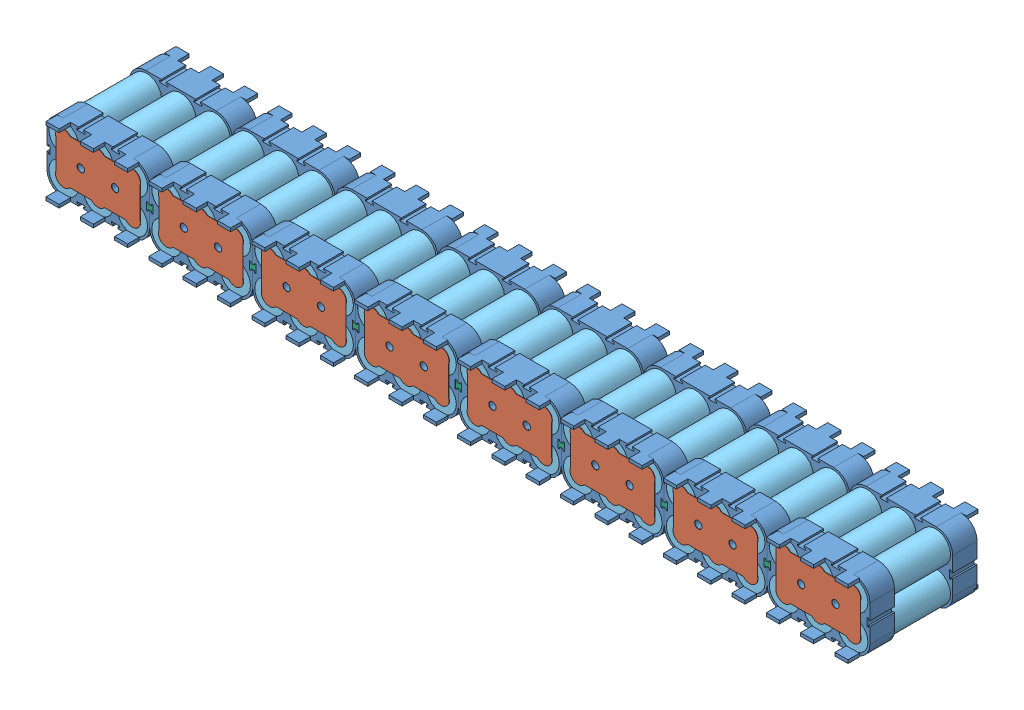
SolidWorks assembly 1S24P_Brick, configuration Default. Lengths in mm.
Overall size (511.31 49.31 71.6).
239 component instances, 6 part files, 3 mates.
Components (placement in the parent):
- 6P_Cell_Pack-1: 6P_Cell_Pack [Default] at origin size (70.31 49.31 71.6)
  - Cell_Holder_6P-1: Cell_Holder_6P [Default] at origin size (63 42 18)
  - Cell_Holder_6P-2: Cell_Holder_6P [Default] at (63 0 -35.6) x (-1 0 0) z (0 0 -1) size (63 42 18)
  - Contact_Plate-1: Contact_Plate [Default] at (5.5 5.515 15) x (1 0 0) z (0 -1 0) size (52 0.2 30.97)
  - Contact_Plate-2: Contact_Plate [Default] at (5.5 5.515 -50.8) x (1 0 0) z (0 -1 0) size (52 0.2 30.97)
  - 18650_wrapped-1: 18650_wrapped [Default] at (10.5 31.5 14.75) x (0.990631 -0.136562 0) z (0.136562 0.990631 0) size (25.12 65.6 25.12)
    - 18650-1: 18650 [Default] at origin size (18 65 18)
    - Insulator_donut-1: Insulator_donut [Default] at (0 64.8 0) x (0.970599 0 -0.240704) z (0.240704 0 0.970599) size (18 0.3 18)
    - 18650_Shrinkwarp-1: 18650_Shrinkwarp [Default] x (0.480873 0 0.87679) z (-0.87679 0 0.480873) size (18.5 65.6 18.5)
  - 18650_wrapped-2: 18650_wrapped [Default] at (31.5 31.5 14.75) x (0.990631 -0.136562 0) z (0.136562 0.990631 0) size (25.12 65.6 25.12)
    - 18650-1: 18650 [Default] at origin size (18 65 18)
    - Insulator_donut-1: Insulator_donut [Default] at (0 64.8 0) x (0.970599 0 -0.240704) z (0.240704 0 0.970599) size (18 0.3 18)
    - 18650_Shrinkwarp-1: 18650_Shrinkwarp [Default] x (0.480873 0 0.87679) z (-0.87679 0 0.480873) size (18.5 65.6 18.5)
  - 18650_wrapped-3: 18650_wrapped [Default] at (52.5 31.5 14.75) x (0.990631 -0.136562 0) z (0.136562 0.990631 0) size (25.12 65.6 25.12)
    - 18650-1: 18650 [Default] at origin size (18 65 18)
    - Insulator_donut-1: Insulator_donut [Default] at (0 64.8 0) x (0.970599 0 -0.240704) z (0.240704 0 0.970599) size (18 0.3 18)
    - 18650_Shrinkwarp-1: 18650_Shrinkwarp [Default] x (0.480873 0 0.87679) z (-0.87679 0 0.480873) size (18.5 65.6 18.5)
  - 18650_wrapped-4: 18650_wrapped [Default] at (10.5 10.5 14.75) x (0.990631 -0.136562 0) z (0.136562 0.990631 0) size (25.12 65.6 25.12)
    - 18650-1: 18650 [Default] at origin size (18 65 18)
    - Insulator_donut-1: Insulator_donut [Default] at (0 64.8 0) x (0.970599 0 -0.240704) z (0.240704 0 0.970599) size (18 0.3 18)
    - 18650_Shrinkwarp-1: 18650_Shrinkwarp [Default] x (0.480873 0 0.87679) z (-0.87679 0 0.480873) size (18.5 65.6 18.5)
  - 18650_wrapped-5: 18650_wrapped [Default] at (31.5 10.5 14.75) x (0.990631 -0.136562 0) z (0.136562 0.990631 0) size (25.12 65.6 25.12)
    - 18650-1: 18650 [Default] at origin size (18 65 18)
    - Insulator_donut-1: Insulator_donut [Default] at (0 64.8 0) x (0.970599 0 -0.240704) z (0.240704 0 0.970599) size (18 0.3 18)
    - 18650_Shrinkwarp-1: 18650_Shrinkwarp [Default] x (0.480873 0 0.87679) z (-0.87679 0 0.480873) size (18.5 65.6 18.5)
  - 18650_wrapped-6: 18650_wrapped [Default] at (52.5 10.5 14.75) x (0.990631 -0.136562 0) z (0.136562 0.990631 0) size (25.12 65.6 25.12)
    - 18650-1: 18650 [Default] at origin size (18 65 18)
    - Insulator_donut-1: Insulator_donut [Default] at (0 64.8 0) x (0.970599 0 -0.240704) z (0.240704 0 0.970599) size (18 0.3 18)
    - 18650_Shrinkwarp-1: 18650_Shrinkwarp [Default] x (0.480873 0 0.87679) z (-0.87679 0 0.480873) size (18.5 65.6 18.5)
- 6P_Cell_Pack-3: 6P_Cell_Pack [Default] at (-63 0 0) size (70.31 49.31 71.6)
  - Cell_Holder_6P-1: Cell_Holder_6P [Default] at origin size (63 42 18)
  - Cell_Holder_6P-2: Cell_Holder_6P [Default] at (63 0 -35.6) x (-1 0 0) z (0 0 -1) size (63 42 18)
  - Contact_Plate-1: Contact_Plate [Default] at (5.5 5.515 15) x (1 0 0) z (0 -1 0) size (52 0.2 30.97)
  - Contact_Plate-2: Contact_Plate [Default] at (5.5 5.515 -50.8) x (1 0 0) z (0 -1 0) size (52 0.2 30.97)
  - 18650_wrapped-1: 18650_wrapped [Default] at (10.5 31.5 14.75) x (0.990631 -0.136562 0) z (0.136562 0.990631 0) size (25.12 65.6 25.12)
    - 18650-1: 18650 [Default] at origin size (18 65 18)
    - Insulator_donut-1: Insulator_donut [Default] at (0 64.8 0) x (0.970599 0 -0.240704) z (0.240704 0 0.970599) size (18 0.3 18)
    - 18650_Shrinkwarp-1: 18650_Shrinkwarp [Default] x (0.480873 0 0.87679) z (-0.87679 0 0.480873) size (18.5 65.6 18.5)
  - 18650_wrapped-2: 18650_wrapped [Default] at (31.5 31.5 14.75) x (0.990631 -0.136562 0) z (0.136562 0.990631 0) size (25.12 65.6 25.12)
    - 18650-1: 18650 [Default] at origin size (18 65 18)
    - Insulator_donut-1: Insulator_donut [Default] at (0 64.8 0) x (0.970599 0 -0.240704) z (0.240704 0 0.970599) size (18 0.3 18)
    - 18650_Shrinkwarp-1: 18650_Shrinkwarp [Default] x (0.480873 0 0.87679) z (-0.87679 0 0.480873) size (18.5 65.6 18.5)
  - 18650_wrapped-3: 18650_wrapped [Default] at (52.5 31.5 14.75) x (0.990631 -0.136562 0) z (0.136562 0.990631 0) size (25.12 65.6 25.12)
    - 18650-1: 18650 [Default] at origin size (18 65 18)
    - Insulator_donut-1: Insulator_donut [Default] at (0 64.8 0) x (0.970599 0 -0.240704) z (0.240704 0 0.970599) size (18 0.3 18)
    - 18650_Shrinkwarp-1: 18650_Shrinkwarp [Default] x (0.480873 0 0.87679) z (-0.87679 0 0.480873) size (18.5 65.6 18.5)
  - 18650_wrapped-4: 18650_wrapped [Default] at (10.5 10.5 14.75) x (0.990631 -0.136562 0) z (0.136562 0.990631 0) size (25.12 65.6 25.12)
    - 18650-1: 18650 [Default] at origin size (18 65 18)
    - Insulator_donut-1: Insulator_donut [Default] at (0 64.8 0) x (0.970599 0 -0.240704) z (0.240704 0 0.970599) size (18 0.3 18)
    - 18650_Shrinkwarp-1: 18650_Shrinkwarp [Default] x (0.480873 0 0.87679) z (-0.87679 0 0.480873) size (18.5 65.6 18.5)
  - 18650_wrapped-5: 18650_wrapped [Default] at (31.5 10.5 14.75) x (0.990631 -0.136562 0) z (0.136562 0.990631 0) size (25.12 65.6 25.12)
    - 18650-1: 18650 [Default] at origin size (18 65 18)
    - Insulator_donut-1: Insulator_donut [Default] at (0 64.8 0) x (0.970599 0 -0.240704) z (0.240704 0 0.970599) size (18 0.3 18)
    - 18650_Shrinkwarp-1: 18650_Shrinkwarp [Default] x (0.480873 0 0.87679) z (-0.87679 0 0.480873) size (18.5 65.6 18.5)
  - 18650_wrapped-6: 18650_wrapped [Default] at (52.5 10.5 14.75) x (0.990631 -0.136562 0) z (0.136562 0.990631 0) size (25.12 65.6 25.12)
    - 18650-1: 18650 [Default] at origin size (18 65 18)
    - Insulator_donut-1: Insulator_donut [Default] at (0 64.8 0) x (0.970599 0 -0.240704) z (0.240704 0 0.970599) size (18 0.3 18)
    - 18650_Shrinkwarp-1: 18650_Shrinkwarp [Default] x (0.480873 0 0.87679) z (-0.87679 0 0.480873) size (18.5 65.6 18.5)
- 6P_Cell_Pack-4: 6P_Cell_Pack [Default] at (-126 0 0) size (70.31 49.31 71.6)
  - Cell_Holder_6P-1: Cell_Holder_6P [Default] at origin size (63 42 18)
  - Cell_Holder_6P-2: Cell_Holder_6P [Default] at (63 0 -35.6) x (-1 0 0) z (0 0 -1) size (63 42 18)
  - Contact_Plate-1: Contact_Plate [Default] at (5.5 5.515 15) x (1 0 0) z (0 -1 0) size (52 0.2 30.97)
  - Contact_Plate-2: Contact_Plate [Default] at (5.5 5.515 -50.8) x (1 0 0) z (0 -1 0) size (52 0.2 30.97)
  - 18650_wrapped-1: 18650_wrapped [Default] at (10.5 31.5 14.75) x (0.990631 -0.136562 0) z (0.136562 0.990631 0) size (25.12 65.6 25.12)
    - 18650-1: 18650 [Default] at origin size (18 65 18)
    - Insulator_donut-1: Insulator_donut [Default] at (0 64.8 0) x (0.970599 0 -0.240704) z (0.240704 0 0.970599) size (18 0.3 18)
    - 18650_Shrinkwarp-1: 18650_Shrinkwarp [Default] x (0.480873 0 0.87679) z (-0.87679 0 0.480873) size (18.5 65.6 18.5)
  - 18650_wrapped-2: 18650_wrapped [Default] at (31.5 31.5 14.75) x (0.990631 -0.136562 0) z (0.136562 0.990631 0) size (25.12 65.6 25.12)
    - 18650-1: 18650 [Default] at origin size (18 65 18)
    - Insulator_donut-1: Insulator_donut [Default] at (0 64.8 0) x (0.970599 0 -0.240704) z (0.240704 0 0.970599) size (18 0.3 18)
    - 18650_Shrinkwarp-1: 18650_Shrinkwarp [Default] x (0.480873 0 0.87679) z (-0.87679 0 0.480873) size (18.5 65.6 18.5)
  - 18650_wrapped-3: 18650_wrapped [Default] at (52.5 31.5 14.75) x (0.990631 -0.136562 0) z (0.136562 0.990631 0) size (25.12 65.6 25.12)
    - 18650-1: 18650 [Default] at origin size (18 65 18)
    - Insulator_donut-1: Insulator_donut [Default] at (0 64.8 0) x (0.970599 0 -0.240704) z (0.240704 0 0.970599) size (18 0.3 18)
    - 18650_Shrinkwarp-1: 18650_Shrinkwarp [Default] x (0.480873 0 0.87679) z (-0.87679 0 0.480873) size (18.5 65.6 18.5)
  - 18650_wrapped-4: 18650_wrapped [Default] at (10.5 10.5 14.75) x (0.990631 -0.136562 0) z (0.136562 0.990631 0) size (25.12 65.6 25.12)
    - 18650-1: 18650 [Default] at origin size (18 65 18)
    - Insulator_donut-1: Insulator_donut [Default] at (0 64.8 0) x (0.970599 0 -0.240704) z (0.240704 0 0.970599) size (18 0.3 18)
    - 18650_Shrinkwarp-1: 18650_Shrinkwarp [Default] x (0.480873 0 0.87679) z (-0.87679 0 0.480873) size (18.5 65.6 18.5)
  - 18650_wrapped-5: 18650_wrapped [Default] at (31.5 10.5 14.75) x (0.990631 -0.136562 0) z (0.136562 0.990631 0) size (25.12 65.6 25.12)
    - 18650-1: 18650 [Default] at origin size (18 65 18)
    - Insulator_donut-1: Insulator_donut [Default] at (0 64.8 0) x (0.970599 0 -0.240704) z (0.240704 0 0.970599) size (18 0.3 18)
    - 18650_Shrinkwarp-1: 18650_Shrinkwarp [Default] x (0.480873 0 0.87679) z (-0.87679 0 0.480873) size (18.5 65.6 18.5)
  - 18650_wrapped-6: 18650_wrapped [Default] at (52.5 10.5 14.75) x (0.990631 -0.136562 0) z (0.136562 0.990631 0) size (25.12 65.6 25.12)
    - 18650-1: 18650 [Default] at origin size (18 65 18)
    - Insulator_donut-1: Insulator_donut [Default] at (0 64.8 0) x (0.970599 0 -0.240704) z (0.240704 0 0.970599) size (18 0.3 18)
    - 18650_Shrinkwarp-1: 18650_Shrinkwarp [Default] x (0.480873 0 0.87679) z (-0.87679 0 0.480873) size (18.5 65.6 18.5)
- 6P_Cell_Pack-5: 6P_Cell_Pack [Default] at (-189 0 0) size (70.31 49.31 71.6)
  - Cell_Holder_6P-1: Cell_Holder_6P [Default] at origin size (63 42 18)
  - Cell_Holder_6P-2: Cell_Holder_6P [Default] at (63 0 -35.6) x (-1 0 0) z (0 0 -1) size (63 42 18)
  - Contact_Plate-1: Contact_Plate [Default] at (5.5 5.515 15) x (1 0 0) z (0 -1 0) size (52 0.2 30.97)
  - Contact_Plate-2: Contact_Plate [Default] at (5.5 5.515 -50.8) x (1 0 0) z (0 -1 0) size (52 0.2 30.97)
  - 18650_wrapped-1: 18650_wrapped [Default] at (10.5 31.5 14.75) x (0.990631 -0.136562 0) z (0.136562 0.990631 0) size (25.12 65.6 25.12)
    - 18650-1: 18650 [Default] at origin size (18 65 18)
    - Insulator_donut-1: Insulator_donut [Default] at (0 64.8 0) x (0.970599 0 -0.240704) z (0.240704 0 0.970599) size (18 0.3 18)
    - 18650_Shrinkwarp-1: 18650_Shrinkwarp [Default] x (0.480873 0 0.87679) z (-0.87679 0 0.480873) size (18.5 65.6 18.5)
  - 18650_wrapped-2: 18650_wrapped [Default] at (31.5 31.5 14.75) x (0.990631 -0.136562 0) z (0.136562 0.990631 0) size (25.12 65.6 25.12)
    - 18650-1: 18650 [Default] at origin size (18 65 18)
    - Insulator_donut-1: Insulator_donut [Default] at (0 64.8 0) x (0.970599 0 -0.240704) z (0.240704 0 0.970599) size (18 0.3 18)
    - 18650_Shrinkwarp-1: 18650_Shrinkwarp [Default] x (0.480873 0 0.87679) z (-0.87679 0 0.480873) size (18.5 65.6 18.5)
  - 18650_wrapped-3: 18650_wrapped [Default] at (52.5 31.5 14.75) x (0.990631 -0.136562 0) z (0.136562 0.990631 0) size (25.12 65.6 25.12)
    - 18650-1: 18650 [Default] at origin size (18 65 18)
    - Insulator_donut-1: Insulator_donut [Default] at (0 64.8 0) x (0.970599 0 -0.240704) z (0.240704 0 0.970599) size (18 0.3 18)
    - 18650_Shrinkwarp-1: 18650_Shrinkwarp [Default] x (0.480873 0 0.87679) z (-0.87679 0 0.480873) size (18.5 65.6 18.5)
  - 18650_wrapped-4: 18650_wrapped [Default] at (10.5 10.5 14.75) x (0.990631 -0.136562 0) z (0.136562 0.990631 0) size (25.12 65.6 25.12)
    - 18650-1: 18650 [Default] at origin size (18 65 18)
    - Insulator_donut-1: Insulator_donut [Default] at (0 64.8 0) x (0.970599 0 -0.240704) z (0.240704 0 0.970599) size (18 0.3 18)
    - 18650_Shrinkwarp-1: 18650_Shrinkwarp [Default] x (0.480873 0 0.87679) z (-0.87679 0 0.480873) size (18.5 65.6 18.5)
  - 18650_wrapped-5: 18650_wrapped [Default] at (31.5 10.5 14.75) x (0.990631 -0.136562 0) z (0.136562 0.990631 0) size (25.12 65.6 25.12)
    - 18650-1: 18650 [Default] at origin size (18 65 18)
    - Insulator_donut-1: Insulator_donut [Default] at (0 64.8 0) x (0.970599 0 -0.240704) z (0.240704 0 0.970599) size (18 0.3 18)
    - 18650_Shrinkwarp-1: 18650_Shrinkwarp [Default] x (0.480873 0 0.87679) z (-0.87679 0 0.480873) size (18.5 65.6 18.5)
  - 18650_wrapped-6: 18650_wrapped [Default] at (52.5 10.5 14.75) x (0.990631 -0.136562 0) z (0.136562 0.990631 0) size (25.12 65.6 25.12)
    - 18650-1: 18650 [Default] at origin size (18 65 18)
    - Insulator_donut-1: Insulator_donut [Default] at (0 64.8 0) x (0.970599 0 -0.240704) z (0.240704 0 0.970599) size (18 0.3 18)
    - 18650_Shrinkwarp-1: 18650_Shrinkwarp [Default] x (0.480873 0 0.87679) z (-0.87679 0 0.480873) size (18.5 65.6 18.5)
- 6P_Cell_Pack-6: 6P_Cell_Pack [Default] at (-252 0 0) size (70.31 49.31 71.6)
  - Cell_Holder_6P-1: Cell_Holder_6P [Default] at origin size (63 42 18)
  - Cell_Holder_6P-2: Cell_Holder_6P [Default] at (63 0 -35.6) x (-1 0 0) z (0 0 -1) size (63 42 18)
  - Contact_Plate-1: Contact_Plate [Default] at (5.5 5.515 15) x (1 0 0) z (0 -1 0) size (52 0.2 30.97)
  - Contact_Plate-2: Contact_Plate [Default] at (5.5 5.515 -50.8) x (1 0 0) z (0 -1 0) size (52 0.2 30.97)
  - 18650_wrapped-1: 18650_wrapped [Default] at (10.5 31.5 14.75) x (0.990631 -0.136562 0) z (0.136562 0.990631 0) size (25.12 65.6 25.12)
    - 18650-1: 18650 [Default] at origin size (18 65 18)
    - Insulator_donut-1: Insulator_donut [Default] at (0 64.8 0) x (0.970599 0 -0.240704) z (0.240704 0 0.970599) size (18 0.3 18)
    - 18650_Shrinkwarp-1: 18650_Shrinkwarp [Default] x (0.480873 0 0.87679) z (-0.87679 0 0.480873) size (18.5 65.6 18.5)
  - 18650_wrapped-2: 18650_wrapped [Default] at (31.5 31.5 14.75) x (0.990631 -0.136562 0) z (0.136562 0.990631 0) size (25.12 65.6 25.12)
    - 18650-1: 18650 [Default] at origin size (18 65 18)
    - Insulator_donut-1: Insulator_donut [Default] at (0 64.8 0) x (0.970599 0 -0.240704) z (0.240704 0 0.970599) size (18 0.3 18)
    - 18650_Shrinkwarp-1: 18650_Shrinkwarp [Default] x (0.480873 0 0.87679) z (-0.87679 0 0.480873) size (18.5 65.6 18.5)
  - 18650_wrapped-3: 18650_wrapped [Default] at (52.5 31.5 14.75) x (0.990631 -0.136562 0) z (0.136562 0.990631 0) size (25.12 65.6 25.12)
    - 18650-1: 18650 [Default] at origin size (18 65 18)
    - Insulator_donut-1: Insulator_donut [Default] at (0 64.8 0) x (0.970599 0 -0.240704) z (0.240704 0 0.970599) size (18 0.3 18)
    - 18650_Shrinkwarp-1: 18650_Shrinkwarp [Default] x (0.480873 0 0.87679) z (-0.87679 0 0.480873) size (18.5 65.6 18.5)
  - 18650_wrapped-4: 18650_wrapped [Default] at (10.5 10.5 14.75) x (0.990631 -0.136562 0) z (0.136562 0.990631 0) size (25.12 65.6 25.12)
    - 18650-1: 18650 [Default] at origin size (18 65 18)
    - Insulator_donut-1: Insulator_donut [Default] at (0 64.8 0) x (0.970599 0 -0.240704) z (0.240704 0 0.970599) size (18 0.3 18)
    - 18650_Shrinkwarp-1: 18650_Shrinkwarp [Default] x (0.480873 0 0.87679) z (-0.87679 0 0.480873) size (18.5 65.6 18.5)
  - 18650_wrapped-5: 18650_wrapped [Default] at (31.5 10.5 14.75) x (0.990631 -0.136562 0) z (0.136562 0.990631 0) size (25.12 65.6 25.12)
    - 18650-1: 18650 [Default] at origin size (18 65 18)
    - Insulator_donut-1: Insulator_donut [Default] at (0 64.8 0) x (0.970599 0 -0.240704) z (0.240704 0 0.970599) size (18 0.3 18)
    - 18650_Shrinkwarp-1: 18650_Shrinkwarp [Default] x (0.480873 0 0.87679) z (-0.87679 0 0.480873) size (18.5 65.6 18.5)
  - 18650_wrapped-6: 18650_wrapped [Default] at (52.5 10.5 14.75) x (0.990631 -0.136562 0) z (0.136562 0.990631 0) size (25.12 65.6 25.12)
    - 18650-1: 18650 [Default] at origin size (18 65 18)
    - Insulator_donut-1: Insulator_donut [Default] at (0 64.8 0) x (0.970599 0 -0.240704) z (0.240704 0 0.970599) size (18 0.3 18)
    - 18650_Shrinkwarp-1: 18650_Shrinkwarp [Default] x (0.480873 0 0.87679) z (-0.87679 0 0.480873) size (18.5 65.6 18.5)
- 6P_Cell_Pack-7: 6P_Cell_Pack [Default] at (-315 0 0) size (70.31 49.31 71.6)
  - Cell_Holder_6P-1: Cell_Holder_6P [Default] at origin size (63 42 18)
  - Cell_Holder_6P-2: Cell_Holder_6P [Default] at (63 0 -35.6) x (-1 0 0) z (0 0 -1) size (63 42 18)
  - Contact_Plate-1: Contact_Plate [Default] at (5.5 5.515 15) x (1 0 0) z (0 -1 0) size (52 0.2 30.97)
  - Contact_Plate-2: Contact_Plate [Default] at (5.5 5.515 -50.8) x (1 0 0) z (0 -1 0) size (52 0.2 30.97)
  - 18650_wrapped-1: 18650_wrapped [Default] at (10.5 31.5 14.75) x (0.990631 -0.136562 0) z (0.136562 0.990631 0) size (25.12 65.6 25.12)
    - 18650-1: 18650 [Default] at origin size (18 65 18)
    - Insulator_donut-1: Insulator_donut [Default] at (0 64.8 0) x (0.970599 0 -0.240704) z (0.240704 0 0.970599) size (18 0.3 18)
    - 18650_Shrinkwarp-1: 18650_Shrinkwarp [Default] x (0.480873 0 0.87679) z (-0.87679 0 0.480873) size (18.5 65.6 18.5)
  - 18650_wrapped-2: 18650_wrapped [Default] at (31.5 31.5 14.75) x (0.990631 -0.136562 0) z (0.136562 0.990631 0) size (25.12 65.6 25.12)
    - 18650-1: 18650 [Default] at origin size (18 65 18)
    - Insulator_donut-1: Insulator_donut [Default] at (0 64.8 0) x (0.970599 0 -0.240704) z (0.240704 0 0.970599) size (18 0.3 18)
    - 18650_Shrinkwarp-1: 18650_Shrinkwarp [Default] x (0.480873 0 0.87679) z (-0.87679 0 0.480873) size (18.5 65.6 18.5)
  - 18650_wrapped-3: 18650_wrapped [Default] at (52.5 31.5 14.75) x (0.990631 -0.136562 0) z (0.136562 0.990631 0) size (25.12 65.6 25.12)
    - 18650-1: 18650 [Default] at origin size (18 65 18)
    - Insulator_donut-1: Insulator_donut [Default] at (0 64.8 0) x (0.970599 0 -0.240704) z (0.240704 0 0.970599) size (18 0.3 18)
    - 18650_Shrinkwarp-1: 18650_Shrinkwarp [Default] x (0.480873 0 0.87679) z (-0.87679 0 0.480873) size (18.5 65.6 18.5)
  - 18650_wrapped-4: 18650_wrapped [Default] at (10.5 10.5 14.75) x (0.990631 -0.136562 0) z (0.136562 0.990631 0) size (25.12 65.6 25.12)
    - 18650-1: 18650 [Default] at origin size (18 65 18)
    - Insulator_donut-1: Insulator_donut [Default] at (0 64.8 0) x (0.970599 0 -0.240704) z (0.240704 0 0.970599) size (18 0.3 18)
    - 18650_Shrinkwarp-1: 18650_Shrinkwarp [Default] x (0.480873 0 0.87679) z (-0.87679 0 0.480873) size (18.5 65.6 18.5)
  - 18650_wrapped-5: 18650_wrapped [Default] at (31.5 10.5 14.75) x (0.990631 -0.136562 0) z (0.136562 0.990631 0) size (25.12 65.6 25.12)
    - 18650-1: 18650 [Default] at origin size (18 65 18)
    - Insulator_donut-1: Insulator_donut [Default] at (0 64.8 0) x (0.970599 0 -0.240704) z (0.240704 0 0.970599) size (18 0.3 18)
    - 18650_Shrinkwarp-1: 18650_Shrinkwarp [Default] x (0.480873 0 0.87679) z (-0.87679 0 0.480873) size (18.5 65.6 18.5)
  - 18650_wrapped-6: 18650_wrapped [Default] at (52.5 10.5 14.75) x (0.990631 -0.136562 0) z (0.136562 0.990631 0) size (25.12 65.6 25.12)
    - 18650-1: 18650 [Default] at origin size (18 65 18)
    - Insulator_donut-1: Insulator_donut [Default] at (0 64.8 0) x (0.970599 0 -0.240704) z (0.240704 0 0.970599) size (18 0.3 18)
    - 18650_Shrinkwarp-1: 18650_Shrinkwarp [Default] x (0.480873 0 0.87679) z (-0.87679 0 0.480873) size (18.5 65.6 18.5)
- 6P_Cell_Pack-8: 6P_Cell_Pack [Default] at (-378 0 0) size (70.31 49.31 71.6)
  - Cell_Holder_6P-1: Cell_Holder_6P [Default] at origin size (63 42 18)
  - Cell_Holder_6P-2: Cell_Holder_6P [Default] at (63 0 -35.6) x (-1 0 0) z (0 0 -1) size (63 42 18)
  - Contact_Plate-1: Contact_Plate [Default] at (5.5 5.515 15) x (1 0 0) z (0 -1 0) size (52 0.2 30.97)
  - Contact_Plate-2: Contact_Plate [Default] at (5.5 5.515 -50.8) x (1 0 0) z (0 -1 0) size (52 0.2 30.97)
  - 18650_wrapped-1: 18650_wrapped [Default] at (10.5 31.5 14.75) x (0.990631 -0.136562 0) z (0.136562 0.990631 0) size (25.12 65.6 25.12)
    - 18650-1: 18650 [Default] at origin size (18 65 18)
    - Insulator_donut-1: Insulator_donut [Default] at (0 64.8 0) x (0.970599 0 -0.240704) z (0.240704 0 0.970599) size (18 0.3 18)
    - 18650_Shrinkwarp-1: 18650_Shrinkwarp [Default] x (0.480873 0 0.87679) z (-0.87679 0 0.480873) size (18.5 65.6 18.5)
  - 18650_wrapped-2: 18650_wrapped [Default] at (31.5 31.5 14.75) x (0.990631 -0.136562 0) z (0.136562 0.990631 0) size (25.12 65.6 25.12)
    - 18650-1: 18650 [Default] at origin size (18 65 18)
    - Insulator_donut-1: Insulator_donut [Default] at (0 64.8 0) x (0.970599 0 -0.240704) z (0.240704 0 0.970599) size (18 0.3 18)
    - 18650_Shrinkwarp-1: 18650_Shrinkwarp [Default] x (0.480873 0 0.87679) z (-0.87679 0 0.480873) size (18.5 65.6 18.5)
  - 18650_wrapped-3: 18650_wrapped [Default] at (52.5 31.5 14.75) x (0.990631 -0.136562 0) z (0.136562 0.990631 0) size (25.12 65.6 25.12)
    - 18650-1: 18650 [Default] at origin size (18 65 18)
    - Insulator_donut-1: Insulator_donut [Default] at (0 64.8 0) x (0.970599 0 -0.240704) z (0.240704 0 0.970599) size (18 0.3 18)
    - 18650_Shrinkwarp-1: 18650_Shrinkwarp [Default] x (0.480873 0 0.87679) z (-0.87679 0 0.480873) size (18.5 65.6 18.5)
  - 18650_wrapped-4: 18650_wrapped [Default] at (10.5 10.5 14.75) x (0.990631 -0.136562 0) z (0.136562 0.990631 0) size (25.12 65.6 25.12)
    - 18650-1: 18650 [Default] at origin size (18 65 18)
    - Insulator_donut-1: Insulator_donut [Default] at (0 64.8 0) x (0.970599 0 -0.240704) z (0.240704 0 0.970599) size (18 0.3 18)
    - 18650_Shrinkwarp-1: 18650_Shrinkwarp [Default] x (0.480873 0 0.87679) z (-0.87679 0 0.480873) size (18.5 65.6 18.5)
  - 18650_wrapped-5: 18650_wrapped [Default] at (31.5 10.5 14.75) x (0.990631 -0.136562 0) z (0.136562 0.990631 0) size (25.12 65.6 25.12)
    - 18650-1: 18650 [Default] at origin size (18 65 18)
    - Insulator_donut-1: Insulator_donut [Default] at (0 64.8 0) x (0.970599 0 -0.240704) z (0.240704 0 0.970599) size (18 0.3 18)
    - 18650_Shrinkwarp-1: 18650_Shrinkwarp [Default] x (0.480873 0 0.87679) z (-0.87679 0 0.480873) size (18.5 65.6 18.5)
  - 18650_wrapped-6: 18650_wrapped [Default] at (52.5 10.5 14.75) x (0.990631 -0.136562 0) z (0.136562 0.990631 0) size (25.12 65.6 25.12)
    - 18650-1: 18650 [Default] at origin size (18 65 18)
    - Insulator_donut-1: Insulator_donut [Default] at (0 64.8 0) x (0.970599 0 -0.240704) z (0.240704 0 0.970599) size (18 0.3 18)
    - 18650_Shrinkwarp-1: 18650_Shrinkwarp [Default] x (0.480873 0 0.87679) z (-0.87679 0 0.480873) size (18.5 65.6 18.5)
- 6P_Cell_Pack-9: 6P_Cell_Pack [Default] at (-441 0 0) size (70.31 49.31 71.6)
  - Cell_Holder_6P-1: Cell_Holder_6P [Default] at origin size (63 42 18)
  - Cell_Holder_6P-2: Cell_Holder_6P [Default] at (63 0 -35.6) x (-1 0 0) z (0 0 -1) size (63 42 18)
  - Contact_Plate-1: Contact_Plate [Default] at (5.5 5.515 15) x (1 0 0) z (0 -1 0) size (52 0.2 30.97)
  - Contact_Plate-2: Contact_Plate [Default] at (5.5 5.515 -50.8) x (1 0 0) z (0 -1 0) size (52 0.2 30.97)
  - 18650_wrapped-1: 18650_wrapped [Default] at (10.5 31.5 14.75) x (0.990631 -0.136562 0) z (0.136562 0.990631 0) size (25.12 65.6 25.12)
    - 18650-1: 18650 [Default] at origin size (18 65 18)
    - Insulator_donut-1: Insulator_donut [Default] at (0 64.8 0) x (0.970599 0 -0.240704) z (0.240704 0 0.970599) size (18 0.3 18)
    - 18650_Shrinkwarp-1: 18650_Shrinkwarp [Default] x (0.480873 0 0.87679) z (-0.87679 0 0.480873) size (18.5 65.6 18.5)
  - 18650_wrapped-2: 18650_wrapped [Default] at (31.5 31.5 14.75) x (0.990631 -0.136562 0) z (0.136562 0.990631 0) size (25.12 65.6 25.12)
    - 18650-1: 18650 [Default] at origin size (18 65 18)
    - Insulator_donut-1: Insulator_donut [Default] at (0 64.8 0) x (0.970599 0 -0.240704) z (0.240704 0 0.970599) size (18 0.3 18)
    - 18650_Shrinkwarp-1: 18650_Shrinkwarp [Default] x (0.480873 0 0.87679) z (-0.87679 0 0.480873) size (18.5 65.6 18.5)
  - 18650_wrapped-3: 18650_wrapped [Default] at (52.5 31.5 14.75) x (0.990631 -0.136562 0) z (0.136562 0.990631 0) size (25.12 65.6 25.12)
    - 18650-1: 18650 [Default] at origin size (18 65 18)
    - Insulator_donut-1: Insulator_donut [Default] at (0 64.8 0) x (0.970599 0 -0.240704) z (0.240704 0 0.970599) size (18 0.3 18)
    - 18650_Shrinkwarp-1: 18650_Shrinkwarp [Default] x (0.480873 0 0.87679) z (-0.87679 0 0.480873) size (18.5 65.6 18.5)
  - 18650_wrapped-4: 18650_wrapped [Default] at (10.5 10.5 14.75) x (0.990631 -0.136562 0) z (0.136562 0.990631 0) size (25.12 65.6 25.12)
    - 18650-1: 18650 [Default] at origin size (18 65 18)
    - Insulator_donut-1: Insulator_donut [Default] at (0 64.8 0) x (0.970599 0 -0.240704) z (0.240704 0 0.970599) size (18 0.3 18)
    - 18650_Shrinkwarp-1: 18650_Shrinkwarp [Default] x (0.480873 0 0.87679) z (-0.87679 0 0.480873) size (18.5 65.6 18.5)
  - 18650_wrapped-5: 18650_wrapped [Default] at (31.5 10.5 14.75) x (0.990631 -0.136562 0) z (0.136562 0.990631 0) size (25.12 65.6 25.12)
    - 18650-1: 18650 [Default] at origin size (18 65 18)
    - Insulator_donut-1: Insulator_donut [Default] at (0 64.8 0) x (0.970599 0 -0.240704) z (0.240704 0 0.970599) size (18 0.3 18)
    - 18650_Shrinkwarp-1: 18650_Shrinkwarp [Default] x (0.480873 0 0.87679) z (-0.87679 0 0.480873) size (18.5 65.6 18.5)
  - 18650_wrapped-6: 18650_wrapped [Default] at (52.5 10.5 14.75) x (0.990631 -0.136562 0) z (0.136562 0.990631 0) size (25.12 65.6 25.12)
    - 18650-1: 18650 [Default] at origin size (18 65 18)
    - Insulator_donut-1: Insulator_donut [Default] at (0 64.8 0) x (0.970599 0 -0.240704) z (0.240704 0 0.970599) size (18 0.3 18)
    - 18650_Shrinkwarp-1: 18650_Shrinkwarp [Default] x (0.480873 0 0.87679) z (-0.87679 0 0.480873) size (18.5 65.6 18.5)
- Cell_Holder_connector-1: Cell_Holder_connector [Default] at (-380 23.5 -50.6) x (0 -1 0) z (-1 0 0) size (5 65.5 4)
- Cell_Holder_connector-2: Cell_Holder_connector [Default] at (-317 23.5 -50.6) x (0 -1 0) z (-1 0 0) size (5 65.5 4)
- Cell_Holder_connector-3: Cell_Holder_connector [Default] at (-254 23.5 -50.6) x (0 -1 0) z (-1 0 0) size (5 65.5 4)
- Cell_Holder_connector-4: Cell_Holder_connector [Default] at (-191 23.5 -50.6) x (0 -1 0) z (-1 0 0) size (5 65.5 4)
- Cell_Holder_connector-5: Cell_Holder_connector [Default] at (-128 23.5 -50.6) x (0 -1 0) z (-1 0 0) size (5 65.5 4)
- Cell_Holder_connector-6: Cell_Holder_connector [Default] at (-65 23.5 -50.6) x (0 -1 0) z (-1 0 0) size (5 65.5 4)
- Cell_Holder_connector-7: Cell_Holder_connector [Default] at (-2 23.5 -50.6) x (0 -1 0) z (-1 0 0) size (5 65.5 4)
Mates (geometry in assembly coordinates):
- Coincident1: coincident: plane of assembly; plane of assembly; plane of 6P_Cell_Pack-8/Cell_Holder_6P-2 through (-376 18.5 -57.6) normal (-1 0 0); plane of Cell_Holder_connector-1 through (-376 18.5 14.9) normal (1 0 0)
- Coincident2: coincident: plane of assembly; plane of assembly; plane of 6P_Cell_Pack-8/Cell_Holder_6P-2 through (-377 22.5 -57.6) normal (0 -1 0); plane of Cell_Holder_connector-1 through (-377.3333 22.5 14.9) normal (0 1 0)
- Coincident3: coincident: plane of assembly; plane of assembly; plane of 6P_Cell_Pack-8/Cell_Holder_6P-2 through (-315 0 -50.6) normal (0 0 -1); plane of Cell_Holder_connector-1 through (-380 23.5 -50.6) normal (0 0 -1)
